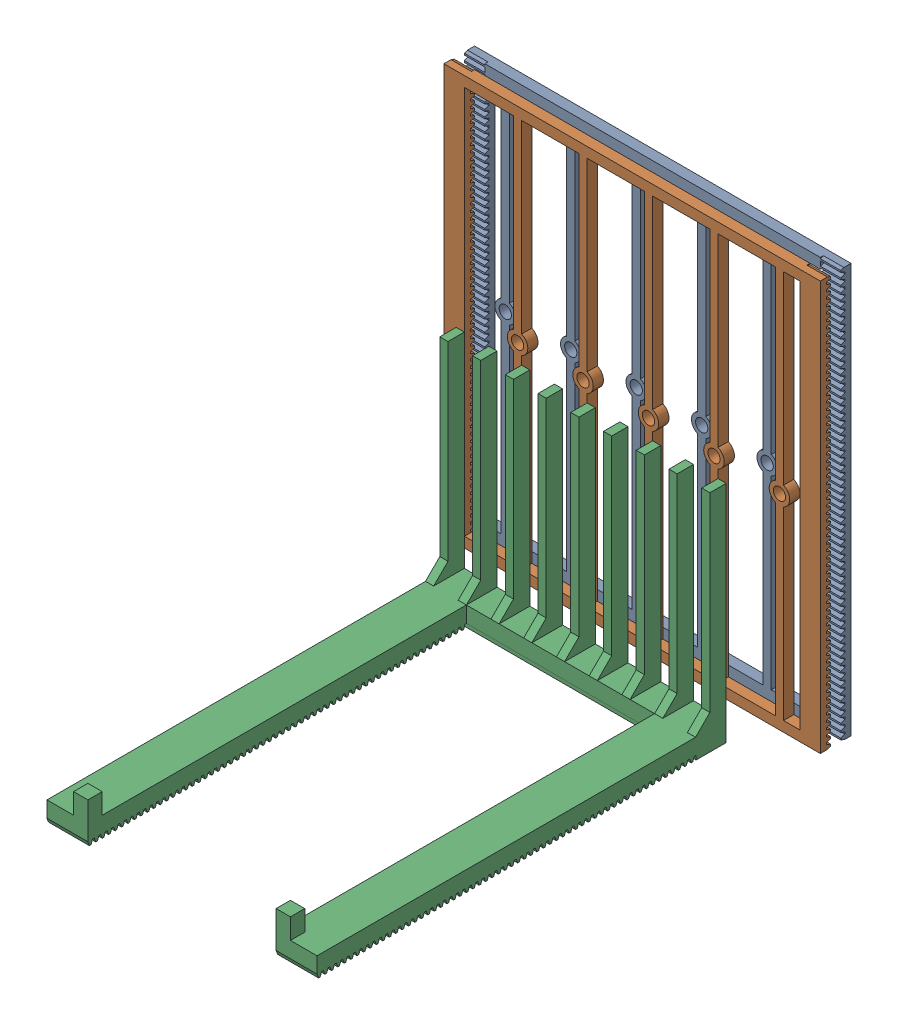
SolidWorks assembly Heddle Assembly, configuration Default. Lengths in mm.
Overall size (184 200 235).
3 component instances, 2 part files, 5 mates.
Components (placement in the parent):
- heddle-1: heddle [Default] at (-59.5785 -15.1983 39.2643) size (184 200 5)
- heddle-2: heddle [Default] at (-59.5785 -15.1983 54.2643) x (-1 0 0) z (0 0 -1) size (184 200 5)
- legoPushPart-1: legoPushPart [Default] at (24.4849 -113.555 165.1016) size (132 109.76 200)
Mates (geometry in assembly coordinates):
- Distance1: distance = 0 mm aligned: plane of heddle-2 through (32.4215 84.8017 49.2643) normal (1 0 0); plane of heddle-1 through (32.4215 84.8017 44.2643) normal (1 0 0)
- Distance2: distance = 0 mm aligned: plane of heddle-2 through (-151.5785 84.8017 49.2643) normal (0 1 0); plane of heddle-1 through (32.4215 84.8017 44.2643) normal (0 1 0)
- Distance3: distance = 15 mm anti-aligned: plane of heddle-2 through (-59.5785 -15.1983 54.2643) normal (0 0 1); plane of heddle-1 through (-59.5785 -15.1983 39.2643) normal (0 0 -1)
- Distance4: distance = 20 mm anti-aligned: plane of legoPushPart-1 through (-125.5785 -103.795 74.2643) normal (0 0 -1); plane of heddle-2 through (-59.5785 -15.1983 54.2643) normal (0 0 1)
- Width1: width anti-aligned: plane of heddle-2 through (-151.5785 84.8017 49.2643) normal (-1 0 0); plane of heddle-2 through (32.4215 84.8017 49.2643) normal (1 0 0); plane of legoPushPart-1 through (6.4215 -103.795 74.2643) normal (1 0 0); plane of legoPushPart-1 through (-125.5785 -103.795 274.2643) normal (-1 0 0)
